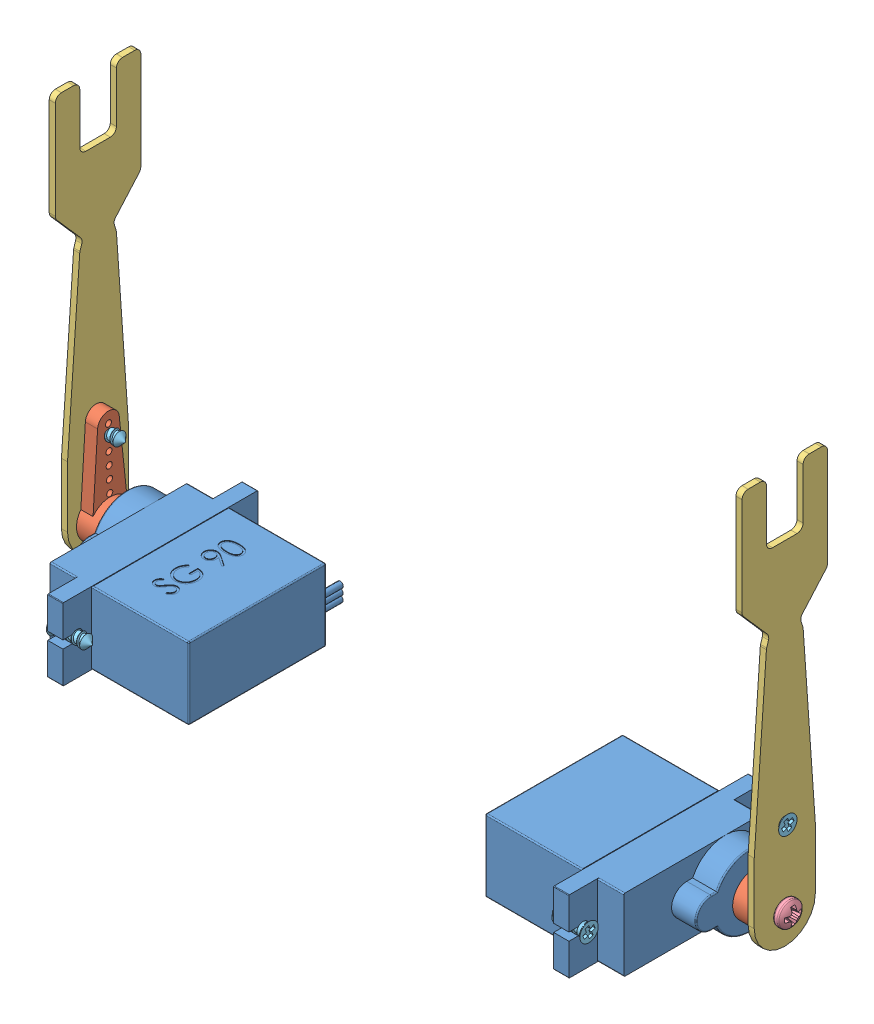
SolidWorks assembly AR, configuration Predeterminado. Lengths in mm.
Overall size (116.68 68.75 31.9).
14 component instances, 5 part files, 28 mates.
Components (placement in the parent):
- sg90-1: sg90 [Default] at (175.3764 -204.8635 98.9775) x (0 0 1) z (0 1 0) size (31.9 29.9 11.8)
- sg90-2: sg90 [Default] at (126.818 -193.0635 98.9775) x (0 0 1) z (0 -1 0) size (31.9 29.9 11.8)
- SG90 plastic Horn-1: SG90 plastic Horn [Default] at (204.8264 -198.9635 104.8775) x (0 0.999858 0.016879) z (0 0.016879 -0.999858) size (19.4 4 7.07)
- SG90 plastic Horn-2: SG90 plastic Horn [Default] at (97.368 -198.9635 104.8775) x (0 0.999767 0.021606) z (0 -0.021606 0.999767) size (19.4 4 7.07)
- Arm-1: Arm [Predeterminado] at (207.8264 -183.2019 150.0835) x (0 0 -1) z (1 0 0) size (14 67.85 1)
- Arm-2: Arm [Predeterminado] at (94.368 -183.2019 59.6715) x (0 0 1) z (-1 0 0) size (14 67.85 1)
- (M2_3_mm)_90116A007_METRIC 316 SS PAN HEAD PHILLIPS MACHINE SCREW-1: (M2_3_mm)_90116A007_METRIC 316 SS PAN HEAD PHILLIPS MACHINE SCREW [90116A007] at (204.8264 -198.9635 104.8775) x (0 0 -1) z (1 0 0) size (4 4 4.68)
- (M2_3_mm)_90116A007_METRIC 316 SS PAN HEAD PHILLIPS MACHINE SCREW-2: (M2_3_mm)_90116A007_METRIC 316 SS PAN HEAD PHILLIPS MACHINE SCREW [90116A007] at (97.368 -198.9635 104.8775) x (0 0 1) z (-1 0 0) size (4 4 4.68)
- M2x6 SelfTap Screw-1: M2x6 SelfTap Screw [Predeterminado] at (93.868 -186.4635 104.8775) x (0 0.924225 0.381849) z (-1 0 0) size (3.4 3.28 6)
- M2x6 SelfTap Screw-2: M2x6 SelfTap Screw [Predeterminado] at (208.3264 -186.4635 104.8775) x (0 -0.924225 -0.381849) z (1 0 0) size (3.4 3.28 6)
- M2x6 SelfTap Screw-3: M2x6 SelfTap Screw [Predeterminado] at (107.418 -198.9635 123.8775) x (0 0.924225 0.381849) z (-1 0 0) size (3.4 3.28 6)
- M2x6 SelfTap Screw-4: M2x6 SelfTap Screw [Predeterminado] at (194.7764 -198.9635 123.8775) x (0 -0.924225 -0.381849) z (1 0 0) size (3.4 3.28 6)
- M2x6 SelfTap Screw-5: M2x6 SelfTap Screw [Predeterminado] at (107.418 -198.9635 96.5775) x (0 0.924225 0.381849) z (-1 0 0) size (3.4 3.28 6)
- M2x6 SelfTap Screw-6: M2x6 SelfTap Screw [Predeterminado] at (194.7764 -198.9635 96.5775) x (0 -0.924225 -0.381849) z (1 0 0) size (3.4 3.28 6)
Mates (geometry in assembly coordinates):
- Coincidente272: coincident: plane of sg90-1 through (205.2764 -198.9635 104.8775) normal (1 0 0); plane of SG90 plastic Horn-1 through (205.2764 -197.7187 104.8985) normal (-1 0 0)
- Concéntrica139: concentric: circle of sg90-1; circle of SG90 plastic Horn-1
- Concéntrica154: concentric: circle of sg90-1; circle of M2x6 SelfTap Screw-6
- Distancia47: distance = 1 mm: plane of M2x6 SelfTap Screw-6 through (194.7764 -198.9635 96.5775) normal (1 0 0); plane of sg90-1 through (193.7764 -204.8635 94.2775) normal (1 0 0)
- Concéntrica155: concentric: circle of sg90-1; circle of M2x6 SelfTap Screw-4
- Distancia48: distance = 1 mm: plane of M2x6 SelfTap Screw-4 through (194.7764 -198.9635 123.8775) normal (1 0 0); plane of sg90-1 through (193.7764 -193.0635 126.1775) normal (1 0 0)
- Coincidente273: coincident: plane of sg90-2 through (96.918 -198.9635 104.8775) normal (-1 0 0); plane of SG90 plastic Horn-2 through (96.918 -197.7188 104.9044) normal (1 0 0)
- Concéntrica140: concentric: circle of sg90-2; circle of SG90 plastic Horn-2
- Concéntrica156: concentric: circle of sg90-2; circle of M2x6 SelfTap Screw-5
- Distancia49: distance = 1 mm: plane of M2x6 SelfTap Screw-5 through (107.418 -198.9635 96.5775) normal (-1 0 0); plane of sg90-2 through (108.418 -193.0635 94.2775) normal (-1 0 0)
- Concéntrica158: concentric: circle of sg90-2; circle of M2x6 SelfTap Screw-3
- Distancia50: distance = 1 mm: plane of M2x6 SelfTap Screw-3 through (107.418 -198.9635 123.8775) normal (-1 0 0); plane of sg90-2 through (108.418 -204.8635 126.1775) normal (-1 0 0)
- Coincidente275: coincident: plane of SG90 plastic Horn-1 through (206.8264 -195.429 104.9372) normal (1 0 0); plane of Arm-1 through (206.8264 -158.9009 101.2558) normal (-1 0 0)
- Concéntrica143: concentric: circle of SG90 plastic Horn-1; circle of Arm-1
- Bloquear1: lock: unknown of SG90 plastic Horn-1; unknown of Arm-1
- Coincidente278: coincident: plane of SG90 plastic Horn-2 through (95.368 -195.4293 104.9539) normal (-1 0 0); plane of Arm-2 through (95.368 -158.9009 108.4991) normal (1 0 0)
- Concéntrica144: concentric: circle of SG90 plastic Horn-2; circle of Arm-2
- Bloquear2: lock: unknown of Arm-2; unknown of SG90 plastic Horn-2
- Bloquear3: lock: unknown of Arm-2; unknown of SG90 plastic Horn-2
- Bloquear4: lock: unknown of SG90 plastic Horn-2; unknown of Arm-2
- Coincidente281: coincident: plane of Arm-1 through (207.8264 -158.9009 101.2558) normal (1 0 0); plane of (M2_3_mm)_90116A007_METRIC 316 SS PAN HEAD PHILLIPS MACHINE SCREW-1 through (207.8264 -198.9635 104.8775) normal (-1 0 0)
- Concéntrica145: concentric: circle of Arm-1; circle of (M2_3_mm)_90116A007_METRIC 316 SS PAN HEAD PHILLIPS MACHINE SCREW-1
- Concéntrica148: concentric: circle of Arm-1; circle of M2x6 SelfTap Screw-2
- Distancia46: distance = 0.5 mm: plane of M2x6 SelfTap Screw-2 through (208.3264 -186.4635 104.8775) normal (1 0 0); plane of Arm-1 through (207.8264 -158.9009 101.2558) normal (1 0 0)
- Coincidente282: coincident: plane of Arm-2 through (94.368 -158.9009 108.4991) normal (-1 0 0); plane of (M2_3_mm)_90116A007_METRIC 316 SS PAN HEAD PHILLIPS MACHINE SCREW-2 through (94.368 -198.9635 104.8775) normal (1 0 0)
- Concéntrica146: concentric: circle of Arm-2; circle of (M2_3_mm)_90116A007_METRIC 316 SS PAN HEAD PHILLIPS MACHINE SCREW-2
- Concéntrica147: concentric: circle of Arm-2; circle of M2x6 SelfTap Screw-1
- Distancia45: distance = 0.5 mm: plane of M2x6 SelfTap Screw-1 through (93.868 -186.4635 104.8775) normal (-1 0 0); plane of Arm-2 through (94.368 -158.9009 108.4991) normal (-1 0 0)
